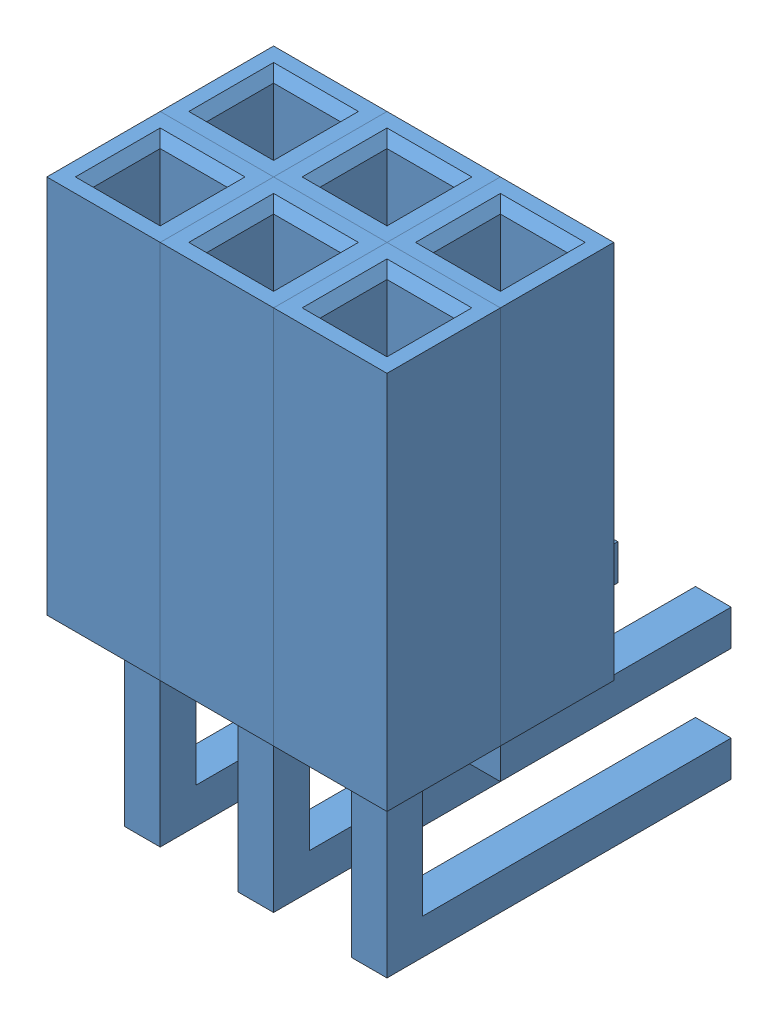
SolidWorks assembly pbd2x3, configuration По умолчанию. Lengths in mm.
Overall size (7.62 12.6 8.58).
6 component instances, 1 part files, 15 mates.
Components (placement in the parent):
- PBS1-1: PBS1 [По умолчанию] at (-3.1437 -1.4395 4.583) size (2.54 10.06 6.04)
- PBS1-2: PBS1 [По умолчанию] at (-0.6037 -1.4395 4.583) size (2.54 10.06 6.04)
- PBS1-3: PBS1 [По умолчанию] at (1.9363 -1.4395 4.583) size (2.54 10.06 6.04)
- PBS1-4: PBS1 [dowble] at (-3.1437 -1.4395 7.123) size (2.54 12.6 8.58)
- PBS1-5: PBS1 [dowble] at (-0.6037 -1.4395 7.123) size (2.54 12.6 8.58)
- PBS1-6: PBS1 [dowble] at (1.9363 -1.4395 7.123) size (2.54 12.6 8.58)
Mates (geometry in assembly coordinates):
- Совпадение1: coincident anti-aligned: plane of PBS1-1 through (-0.6037 7.0605 4.583) normal (1 0 0); plane of PBS1-2 through (-0.6037 7.0605 4.583) normal (-1 0 0)
- Совпадение2: coincident aligned: plane of PBS1-1 through (-3.1437 7.0605 4.583) normal (0 1 0); plane of PBS1-2 through (-0.6037 7.0605 4.583) normal (0 1 0)
- Совпадение3: coincident aligned: plane of PBS1-1 through (-3.1437 7.0605 2.043) normal (0 0 -1); plane of PBS1-2 through (-0.6037 7.0605 2.043) normal (0 0 -1)
- Совпадение4: coincident anti-aligned: plane of PBS1-2 through (1.9363 7.0605 4.583) normal (1 0 0); plane of PBS1-3 through (1.9363 7.0605 4.583) normal (-1 0 0)
- Совпадение5: coincident aligned: plane of PBS1-2 through (-0.6037 7.0605 4.583) normal (0 1 0); plane of PBS1-3 through (1.9363 7.0605 4.583) normal (0 1 0)
- Совпадение6: coincident aligned: plane of PBS1-2 through (-0.6037 7.0605 2.043) normal (0 0 -1); plane of PBS1-3 through (1.9363 7.0605 2.043) normal (0 0 -1)
- Совпадение7: coincident anti-aligned: plane of PBS1-1 through (-3.1437 7.0605 4.583) normal (0 0 1); plane of PBS1-4 through (-3.1437 7.0605 4.583) normal (0 0 -1)
- Совпадение8: coincident aligned: plane of PBS1-1 through (-3.1437 7.0605 4.583) normal (-1 0 0); plane of PBS1-4 through (-3.1437 7.0605 7.123) normal (-1 0 0)
- Совпадение9: coincident aligned: plane of PBS1-1 through (-3.1437 7.0605 4.583) normal (0 1 0); plane of PBS1-4 through (-3.1437 7.0605 7.123) normal (0 1 0)
- Совпадение10: coincident anti-aligned: plane of PBS1-2 through (-0.6037 7.0605 4.583) normal (0 0 1); plane of PBS1-5 through (-0.6037 7.0605 4.583) normal (0 0 -1)
- Совпадение11: coincident anti-aligned: plane of PBS1-4 through (-0.6037 7.0605 7.123) normal (1 0 0); plane of PBS1-5 through (-0.6037 7.0605 7.123) normal (-1 0 0)
- Совпадение12: coincident aligned: plane of PBS1-2 through (-0.6037 7.0605 4.583) normal (0 1 0); plane of PBS1-5 through (-0.6037 7.0605 7.123) normal (0 1 0)
- Совпадение13: coincident anti-aligned: plane of PBS1-3 through (1.9363 7.0605 4.583) normal (0 0 1); plane of PBS1-6 through (1.9363 7.0605 4.583) normal (0 0 -1)
- Совпадение14: coincident anti-aligned: plane of PBS1-5 through (1.9363 7.0605 7.123) normal (1 0 0); plane of PBS1-6 through (1.9363 7.0605 7.123) normal (-1 0 0)
- Совпадение15: coincident aligned: plane of PBS1-3 through (1.9363 7.0605 4.583) normal (0 1 0); plane of PBS1-6 through (1.9363 7.0605 7.123) normal (0 1 0)
